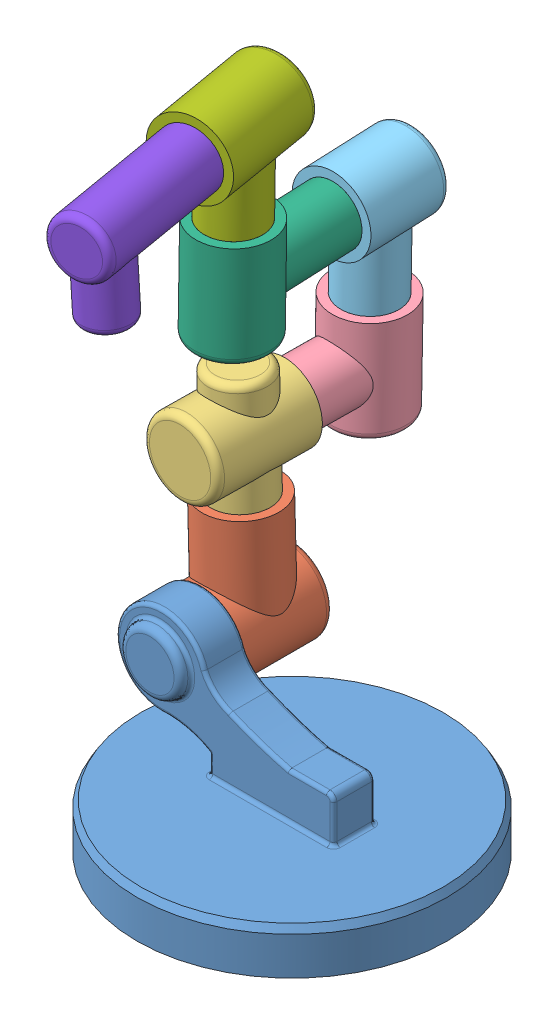
SolidWorks assembly ToyMakerBot, configuration Default. Lengths in mm.
Overall size (450 864.34 562.17).
8 component instances, 8 part files, 12 mates.
Components (placement in the parent):
- link0-1: link0 [Default] at (194.036 66.9391 297.3277) size (450 240 450)
- link1-1: link1 [Default] at (34.036 241.9391 267.3277) x (-0.027027 0.999635 0) z (-0.999635 -0.027027 0) size (210 130 120)
- link2-2: link2 [Default] at (28.6447 471.8774 142.3329) x (-0.027027 0.999635 0) z (0.999554 0.027025 0.012696) size (160 150 110)
- link3-3: link3 [Default] at (28.9133 400.5697 22.3022) x (-0.012691 -0.000343 0.999919) z (-0.999765 0.017584 -0.012683) size (175 150 110)
- link4-1: link4 [Default] at (33.8352 680.5264 22.4607) x (0.998986 -0.01754 -0.041466) z (-0.017578 -0.999845 -0.000566) size (110 120 185)
- link5-1: link5 [Default] at (42.5396 680.2545 232.2801) x (-0.999022 0.015335 0.041464) z (-0.041449 0.001295 -0.99914) size (110 150 205)
- link6-1: link6 [Default] at (33.7059 875.4597 162.0365) x (-0.015376 -0.999882 -0.000658) z (-0.986038 0.015054 0.165836) size (175 150 110)
- link7-1: link7 [Default] at (58.5769 874.9799 309.9595) x (0.05213 -0.998568 -0.012003) z (-0.98478 -0.053399 0.165402) size (152.5 200 85)
Mates (geometry in assembly coordinates):
- Coincident3: coincident aligned: circle of link0-1; circle of link1-1
- Concentric4: concentric aligned: cylinder of link1-1 through (29.9819 391.8843 207.3277) axis (0.027027 -0.999635 0) radius 42.5; cylinder of link2-2 through (25.6576 551.8259 207.3277) axis (0.027027 -0.999635 0) radius 42.5
- Coincident8: coincident aligned: circle of link1-1; circle of link2-2
- Concentric5: concentric anti-aligned: cylinder of link2-2 through (28.6574 471.8778 141.333) axis (-0.012691 -0.000343 0.999919) radius 42.5; cylinder of link3-3 through (28.6447 471.8774 142.3329) axis (0.012691 0.000343 -0.999919) radius 42.5
- Coincident9: coincident aligned: circle of link2-2; circle of link3-3
- Concentric6: concentric aligned: cylinder of link3-3 through (30.0559 465.5596 22.339) axis (0.017578 0.999845 0.000566) radius 42.5; cylinder of link4-1 through (31.55 550.5465 22.3871) axis (0.017578 0.999845 0.000566) radius 42.5
- Coincident10: coincident anti-aligned: circle of link3-3; circle of link4-1
- Concentric7: concentric anti-aligned: cylinder of link4-1 through (38.3947 680.384 132.3661) axis (-0.041449 0.001295 -0.99914) radius 42.5; cylinder of link5-1 through (36.3222 680.4487 82.4091) axis (0.041449 -0.001295 0.99914) radius 42.5
- Coincident11: coincident aligned: circle of link4-1; circle of link5-1
- Coincident12: coincident aligned: circle of link5-1; circle of link6-1
- Coincident14: coincident anti-aligned: plane of link6-1; plane of link7-1 through (58.5769 874.9799 309.9595) normal (-0.165806 0.003198 -0.986153)
- Coincident15: coincident aligned: circle of link6-1; circle of link7-1
